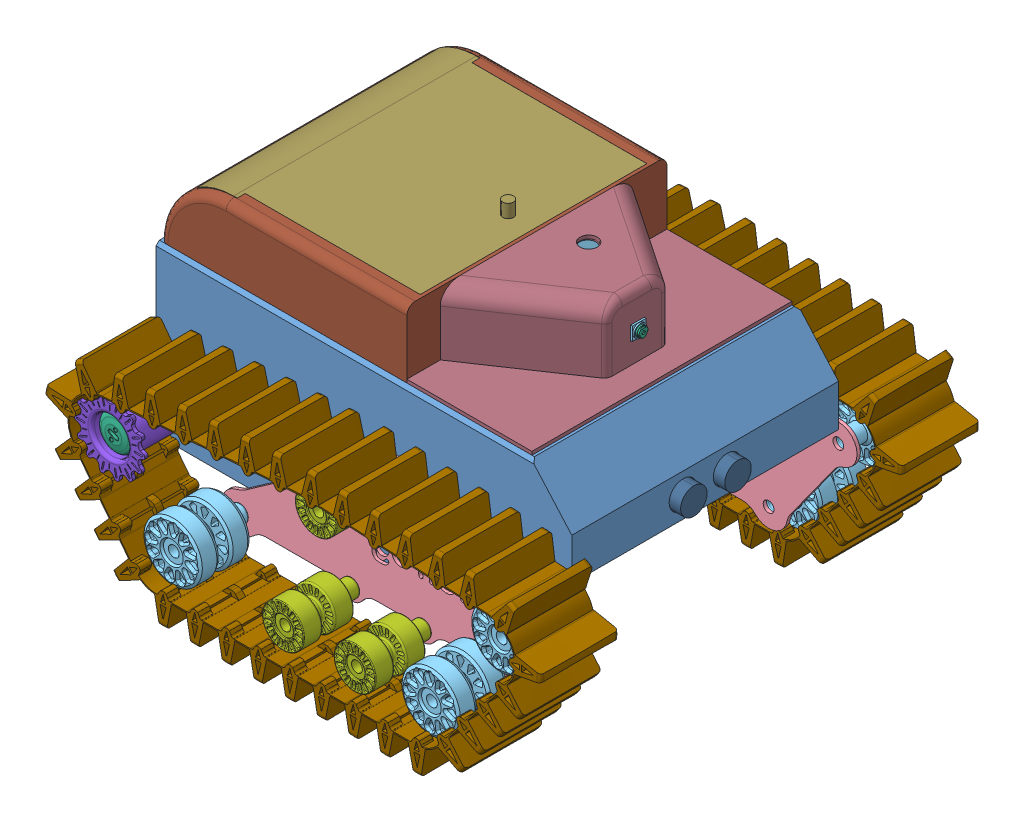
SolidWorks assembly Trial assembly, configuration Standard. Lengths in mm.
Overall size (298.01 241.17 263.94).
72 component instances, 36 part files, 43 mates.
Components (placement in the parent):
- Box-1: Box [Standard] at (-47.2891 -14.6729 181.4058) size (249.41 100 160)
- motor.step-1: motor.step [Standard] at (-130.1233 -32.1815 288.0058) x (-0.999923 0.012371 0) z (0.012371 0.999923 0) size (37.1 151.83 37.1)
- motor.step-2: motor.step [Standard] at (-129.9085 -32.1821 234.7599) x (0.999976 0.006987 0) z (-0.006987 0.999976 0) size (37.1 151.83 37.1)
- Battery-1: Battery [Standard] at (-3.4096 -17.5026 235.416) x (0.999881 0.015399 0) z (0 0 1) size (142 30 52)
- Holder final-2: Holder final [Default] at (-50.5766 -25.9238 343.4058) x (-1 0 0) z (0 0 -1) size (219.16 87.92 2)
- Idler v.1.2-1: Idler v.1.2 [Default] at (98.3421 -14.7039 369.8058) x (0.81006 -0.586348 0) z (0 0 -1) size (35 35 41.41)
- Sprocket Cap-1: Sprocket Cap [Default] at (-129.986 -21.0824 388.018) x (0.928962 -0.370176 0) z (0 0 1) size (21.5 21.5 12.71)
- Idler v.1.2-4: Idler v.1.2 [Default] at (56.5086 -68.4433 369.8058) x (-0.499777 -0.866154 0) z (0 0 -1) size (35 35 41.41)
- Idler v.1.2-5: Idler v.1.2 [Default] at (-98.3153 -68.0135 369.8058) x (-0.81006 0.586348 0) z (0 0 -1) size (35 35 41.41)
- Roller v.1.2-4: Roller v.1.2 [Default] at (-31.4914 -73.0135 369.8058) x (-0.980103 -0.198489 0) z (0 0 -1) size (25 25 41.58)
- Roller v.1.2-5: Roller v.1.2 [Default] at (-11.7449 -3.8443 369.8058) x (-0.912989 0.407984 0) z (0 0 -1) size (25 25 41.58)
- Roller v.1.2-6: Roller v.1.2 [Default] at (11.5086 -73.0135 369.8058) x (-0.63536 0.772216 0) z (0 0 -1) size (25 25 41.58)
- Sprocket1-1: Sprocket1 [Default] at (-129.986 -21.0824 388.3058) x (-0.616135 0.78764 0) z (0 0 1) size (42.28 41.35 44)
- Final Track-2: Final Track [Default] at (-129.986 -21.0824 369.7501) size (298.01 125.81 47.26)
- Holder final-3: Holder final [Default] at (-50.5766 -25.9238 181.4058) x (-1 0 0) z (0 0 -1) size (219.16 87.92 2)
- Idler v.1.2-9: Idler v.1.2 [Default] at (98.3421 -14.7039 153.0058) x (-0.81006 0.586348 0) z (0 0 1) size (35 35 41.41)
- Idler v.1.2-10: Idler v.1.2 [Default] at (-98.3153 -68.0135 153.0058) x (0.81006 -0.586348 0) z (0 0 1) size (35 35 41.41)
- Idler v.1.2-11: Idler v.1.2 [Default] at (56.5086 -68.4433 153.0058) x (0.499777 0.866154 0) z (0 0 1) size (35 35 41.41)
- Sprocket Cap-3: Sprocket Cap [Default] at (-129.986 -21.0824 134.7936) x (-0.928962 0.370176 0) z (0 0 -1) size (21.5 21.5 12.71)
- Final Track-3: Final Track [Default] at (-129.986 -21.0824 153.0615) size (298.01 125.81 47.26)
- Sprocket1-3: Sprocket1 [Default] at (-129.986 -21.0824 134.5058) x (0.616135 -0.78764 0) z (0 0 -1) size (42.28 41.35 44)
- Roller v.1.2-13: Roller v.1.2 [Default] at (11.5086 -73.0135 153.0058) x (0.201521 -0.979484 0) z (0 0 1) size (25 25 41.58)
- Roller v.1.2-14: Roller v.1.2 [Default] at (-31.4914 -73.0135 153.0058) x (0.999965 0.008424 0) z (0 0 1) size (25 25 41.58)
- Roller v.1.2-15: Roller v.1.2 [Default] at (-11.7449 -3.8443 153.0058) x (0.823373 -0.5675 0) z (0 0 1) size (25 25 41.58)
- ultrasonic-sensor.step-1: ultrasonic-sensor.step [Default] at (91.2697 5.3271 261.4058) x (0 0 -1) z (0 -1 0) size (45.3 18.15 26.45)
- Assem3-1: Assem3 [Default] at (-49.8047 45.3076 181.4058) x (1 0 0) z (0 1 0) size (148.5 156 62.98)
  - Compartment - No Tolerance-1: Compartment - No Tolerance [Default] at origin size (148.5 156 55)
  - compartment door - No tolerance-2: compartment door - No tolerance [Default] at (-59.6798 0 -0.0161) x (0 0 1) z (-1 0 0) size (14.5 145.5 129)
- Hood + Mic + Cam-1: Hood + Mic + Cam [Default] at (157.4483 -34.3077 229.7947) x (0.063713 0.2627 0.962772) z (-0.9806 0.195682 0.0115) size (169.43 108 86.1)
  - Hood-1: Hood [Default] at (-14.6815 52.7016 172.1066) x (-0.962772 0.270071 -0.0115) z (-0.063713 -0.185376 0.9806) size (156.01 55 75)
  - Mic.step-1: Mic.step [Default] at (33.7525 61.5998 155.5156) x (-0.2627 -0.944827 -0.195682) z (-0.063713 -0.185376 0.9806) size (41.3 13.35 15.1)
  - RspCamera.stp-1: RspCamera.stp [Default] at (48.9745 63.3299 120.1241) x (-0.2627 -0.944827 -0.195682) z (0.063713 0.185376 -0.9806) size (23.86 25 9.96)
    - 70521906.stp-1: 70521906.stp [Default] at (1.7167 0.8597 0.0159) size (2 2.1 0.95)
      - 70521906_01.stp-1: 70521906_01.stp [Default] at origin size (0.25 0.55 0.75)
      - 70521906_02.stp-1: 70521906_02.stp [Default] at origin size (0.25 0.55 0.75)
      - 70521906_03.stp-1: 70521906_03.stp [Default] at origin size (2 1.25 0.9)
      - 70521906_04.stp-1: 70521906_04.stp [Default] at origin size (0.25 0.55 0.75)
      - 70521906_05.stp-1: 70521906_05.stp [Default] at origin size (0.25 0.55 0.75)
      - 70521906_06.stp-1: 70521906_06.stp [Default] at origin size (0.25 0.55 0.75)
      - 70521906_07.stp-1: 70521906_07.stp [Default] at origin size (0.25 0.55 0.75)
    - PicameraPCB.stp-1: PicameraPCB.stp [Default] at (0.2393 -0.0199 0) x (-1 0 0) z (0 0 1) size (23.86 25 2.2)
    - OVA5647_Housing.stp-1: OVA5647_Housing.stp [Default] at (-2.4078 0.0859 1) x (1 0 0) z (0 -1 0) size (8 3.95 8)
    - OVA5647_Lens_FOV.stp-1: OVA5647_Lens_FOV.stp [Default] at (-2.4087 0.0921 5.963) x (1 0 0) z (0 -1 0) size (6 3.35 6)
    - ribbon_cam.stp-1: ribbon_cam.stp [Default] at (-2.4804 0.3633 1.4162) x (0 1 0) z (1 0 0) size (5.6 0.69 4.76)
    - CCD.stp-1: CCD.stp [Default] at (-2.0757 0.287 1.296) x (1 0 0) z (0 -1 0) size (8.01 0.69 8.01)
    - CAPC-0805-T0.75-BN.stp-1: CAPC-0805-T0.75-BN.stp [Default] at (4.562 5.9833 -0.0026) x (0 -1 0) z (0 0 -1) size (2.1 1.35 0.75)
    - CAPC-0805-T0.75-BN.stp-2: CAPC-0805-T0.75-BN.stp [Default] at (2.0233 10.2705 -0.0026) x (0 -1 0) z (0 0 -1) size (2.1 1.35 0.75)
    - CAPC-0402-T0.55-BN.stp-1: CAPC-0402-T0.55-BN.stp [Default] at (-2.9562 6.224 -0.2572) x (-1 0 0) z (0 -1 0) size (1.05 0.55 0.55)
    - CAPC-0402-T0.55-BN.stp-2: CAPC-0402-T0.55-BN.stp [Default] at (-2.9504 5.2898 -0.2691) x (-1 0 0) z (0 -1 0) size (1.05 0.55 0.55)
    - CAPC-0402-T0.55-BN.stp-3: CAPC-0402-T0.55-BN.stp [Default] at (4.5768 -5.1833 -0.2811) x (-1 0 0) z (0 -1 0) size (1.05 0.55 0.55)
    - CAPC-0402-T0.55-BN.stp-4: CAPC-0402-T0.55-BN.stp [Default] at (2.5547 -5.1368 -0.2811) x (-1 0 0) z (0 -1 0) size (1.05 0.55 0.55)
    - CAPC-0402-T0.55-BN.stp-5: CAPC-0402-T0.55-BN.stp [Default] at (2.6129 -9.93 -0.293) x (-1 0 0) z (0 -1 0) size (1.05 0.55 0.55)
    - CAPC-0402-T0.55-BN.stp-6: CAPC-0402-T0.55-BN.stp [Default] at (4.7286 -9.9294 -0.293) x (-1 0 0) z (0 -1 0) size (1.05 0.55 0.55)
    - CAPC-0402-T0.55-BN.stp-7: CAPC-0402-T0.55-BN.stp [Default] at (8.4068 -3.8793 -0.2811) x (-1 0 0) z (0 -1 0) size (1.05 0.55 0.55)
    - CAPC-0402-T0.55-BN.stp-8: CAPC-0402-T0.55-BN.stp [Default] at (9.0088 0.0217 -0.2796) x (0 1 0) z (-1 0 0) size (1.05 0.55 0.55)
    - CAPC-0402-T0.55-BN.stp-9: CAPC-0402-T0.55-BN.stp [Default] at (10.4284 2.6731 -0.3022) x (0 1 0) z (-1 0 0) size (1.05 0.55 0.55)
    - CAPC-0402-T0.55-BN.stp-10: CAPC-0402-T0.55-BN.stp [Default] at (8.2321 1.3259 -0.2838) x (1 0 0) z (0 1 0) size (1.05 0.55 0.55)
    - RESC-0402.stp-1: RESC-0402.stp [Default] at (3.7919 0.0148 -0.0114) x (1 0 0) z (0 0 -1) size (1.05 0.55 0.4)
    - RESC-0402.stp-2: RESC-0402.stp [Default] at (4.1232 2.6296 -0.0028) x (0 -1 0) z (0 0 -1) size (1.05 0.55 0.4)
    - RESC-0402.stp-3: RESC-0402.stp [Default] at (10.5883 -6.2795 -0.0019) x (0 1 0) z (0 0 -1) size (1.05 0.55 0.4)
    - RESC-0603.stp-1: RESC-0603.stp [Default] at (-2.6191 7.0617 -0.0121) x (1 0 0) z (0 0 -1) size (1.7 0.9 0.55)
    - RESC-0603.stp-2: RESC-0603.stp [Default] at (-3.4466 3.0018 -0.0048) x (0 -1 0) z (0 0 -1) size (1.7 0.9 0.55)
    - RESC-1210.stp-1: RESC-1210.stp [Default] at (2.2265 5.9002 -0.0068) x (0 -1 0) z (0 0 -1) size (3.3 2.7 0.6)
    - c-1-1734248-5-e-raspberry_display.stp-1: c-1-1734248-5-e-raspberry_display.stp [Default] at (-10.6651 0.0449 -1.5) x (0 -1 0) z (-1 0 0) size (22.4 3.22 5.68)
    - SOT23-5.stp-1: SOT23-5.stp [Default] at (4.2989 9.8879 0.5457) x (0 -1 0) z (0 0 -1) size (2.84 3.01 1.19)
    - SOT23-5.stp-2: SOT23-5.stp [Default] at (3.5194 -3.2493 0.04) x (-1 0 0) z (0 0 -1) size (2.84 3.01 1.19)
    - SOT23-5.stp-3: SOT23-5.stp [Default] at (3.5816 -8.055 0.0206) x (-1 0 0) z (0 0 -1) size (2.84 3.01 1.19)
    - KX7 SMD Quartz Crystal Resonator 3.2x2.5mm.stp-1: KX7 SMD Quartz Crystal Resonator 3.2x2.5mm.stp [Default] at (9.9746 -4.9221 0.0339) x (-1 0 0) z (0 -1 0) size (3.2 0.6 2.5)
    - c6aaa.stp-1: c6aaa.stp [Default] at (0.0643 0.0942 0) x (1 0 0) z (0 0 -1) size (2 2.99 0.6)
    - 4pin_smd.stp-1: 4pin_smd.stp [Default] at (0.027 0.0676 0) x (1 0 0) z (0 0 -1) size (1.29 1 0.47)
    - 4pin_smd.stp-2: 4pin_smd.stp [Default] at (-0.0093 -6.0092 -0.0198) x (1 0 0) z (0 0 -1) size (1.29 1 0.47)
    - 4pin_smd.stp-3: 4pin_smd.stp [Default] at (0.0326 -3.0068 -0.0235) x (1 0 0) z (0 0 -1) size (1.29 1 0.47)
Mates (geometry in assembly coordinates):
- Concentric1: concentric: circle of Box-1; cylinder of motor.step-1 through (-129.986 -21.0824 361.8058) axis (0 0 -1) radius 2.95
- Concentric2: concentric anti-aligned: circle of Box-1; circle of motor.step-2
- Coincident1: coincident: plane of Box-1 through (-150.986 -52.6924 341.4058) normal (0 1 0); line of Battery-1 through (-95.6615 -52.6924 287.416) axis (0 0 -1)
- Coincident4: coincident anti-aligned: plane of Box-1 through (-47.2891 -14.6729 341.4058) normal (0 0 1); plane of Holder final Opposite-1 through (98.3421 -14.7039 341.4058) normal (0 0 -1)
- Coincident14: coincident anti-aligned: plane of Box-1 through (-47.2891 -14.6729 339.4058) normal (0 0 -1); plane of motor.step-1 through (-130.1233 -32.1815 339.4058) normal (0 0 1)
- Concentric10: concentric aligned: cylinder of Holder final Opposite-1 through (98.3421 -14.7039 341.4058) axis (0 0 1) radius 3.25; cylinder of Idler v.1.2-1 through (98.3421 -14.7039 384.8058) axis (0 0 1) radius 3.25
- Coincident16: coincident anti-aligned: plane of Holder final Opposite-1 through (98.3421 -14.7039 343.4058) normal (0 0 1); circle of Idler v.1.2-1
- Concentric12: concentric aligned: cylinder of Holder final Opposite-1 through (-98.3153 -68.0135 341.4058) axis (0 0 1) radius 3.25; cylinder of Idler v.1.2-5 through (-98.3153 -68.0135 384.8058) axis (0 0 1) radius 3.25
- Coincident18: coincident anti-aligned: plane of Holder final Opposite-1 through (98.3421 -14.7039 343.4058) normal (0 0 1); circle of Idler v.1.2-5
- Concentric14: concentric aligned: cylinder of Holder final Opposite-1 through (56.5086 -68.4433 341.4058) axis (0 0 1) radius 3.25; cylinder of Idler v.1.2-4 through (56.5086 -68.4433 384.8058) axis (0 0 1) radius 3.25
- Coincident19: coincident anti-aligned: plane of Holder final Opposite-1 through (98.3421 -14.7039 343.4058) normal (0 0 1); circle of Idler v.1.2-4
- Concentric15: concentric anti-aligned: cylinder of Holder final Opposite-1 through (-31.4914 -73.0135 341.4058) axis (0 0 1) radius 3.25; cylinder of Roller v.1.2-4 through (-31.4914 -73.0135 354.8058) axis (0 0 -1) radius 3.25
- Coincident20: coincident anti-aligned: plane of Holder final Opposite-1 through (98.3421 -14.7039 343.4058) normal (0 0 1); circle of Roller v.1.2-4
- Concentric16: concentric anti-aligned: cylinder of Holder final Opposite-1 through (-11.7449 -3.8443 341.4058) axis (0 0 1) radius 3.25; cylinder of Roller v.1.2-5 through (-11.7449 -3.8443 354.8058) axis (0 0 -1) radius 3.25
- Coincident21: coincident anti-aligned: plane of Holder final Opposite-1 through (98.3421 -14.7039 343.4058) normal (0 0 1); circle of Roller v.1.2-5
- Concentric17: concentric anti-aligned: cylinder of Holder final Opposite-1 through (11.5086 -73.0135 341.4058) axis (0 0 1) radius 3.25; cylinder of Roller v.1.2-6 through (11.5086 -73.0135 354.8058) axis (0 0 -1) radius 3.25
- Coincident22: coincident anti-aligned: plane of Holder final Opposite-1 through (98.3421 -14.7039 343.4058) normal (0 0 1); circle of Roller v.1.2-6
- Concentric18: concentric anti-aligned: cylinder of Box-1 through (18.2551 -6.8037 181.4058) axis (0 0 1) radius 1.4; cylinder of Holder final Opposite-1 through (18.2551 -6.8037 343.4058) axis (0 0 -1) radius 1.4
- Concentric19: concentric anti-aligned: cylinder of Box-1 through (-31.4914 -33.4433 181.4058) axis (0 0 1) radius 1.4; cylinder of Holder final Opposite-1 through (-31.4914 -33.4433 343.4058) axis (0 0 -1) radius 1.4
- Coincident23: coincident anti-aligned: plane of motor.step-1 through (-129.986 -21.0824 346.3058) normal (0 0 1); plane of Sprocket1-1 through (-129.986 -21.0824 346.3058) normal (0 0 -1)
- Concentric21: concentric anti-aligned: cylinder of motor.step-1 through (-129.986 -21.0824 361.8058) axis (0 0 -1) radius 2.95; cylinder of Sprocket1-1 through (-129.986 -21.0824 346.3058) axis (0 0 1) radius 3.025
- Concentric22: concentric aligned: cylinder of Sprocket Cap-1 through (-129.986 -21.0824 386.1355) axis (0 0 -1) radius 7.25; cylinder of Sprocket1-1 through (-129.986 -21.0824 353.3058) axis (0 0 -1) radius 11
- Coincident24: coincident anti-aligned: circle of Sprocket Cap-1; plane of Sprocket1-1 through (-129.986 -21.0824 384.3058) normal (0 0 1)
- Concentric23: concentric anti-aligned: cylinder of Idler v.1.2-1 through (98.3421 -14.7039 384.8058) axis (0 0 1) radius 17.5; cylinder of Belt1-1-2 through (98.3421 -14.7039 393.2501) axis (0 0 -1) radius 17.6
- Concentric24: concentric anti-aligned: cylinder of Sprocket1-1 through (-129.986 -21.0824 350.3058) axis (0 0 1) radius 12; cylinder of Belt1-1-2 through (-129.986 -21.0824 393.2501) axis (0 0 -1) radius 21.4
- Parallel2: parallel anti-aligned: plane of Sprocket1-1 through (-147.414 -14.8764 390.3058) normal (-0.725341 -0.68839 0); plane of Belt1-1-2 through (-149.0336 -13.751 386.2501) normal (0.725341 0.68839 0)
- Coincident32: coincident anti-aligned: circle of Box-1; circle of Holder final-3
- Coincident34: coincident anti-aligned: circle of Box-1; circle of Holder final-3
- Coincident35: coincident aligned: cylinder of Holder final-3 through (11.5086 -73.0135 179.4058) axis (0 0 1) radius 3.25; circle of Roller v.1.2-13
- Concentric27: concentric aligned: cylinder of Holder final-3 through (-31.4914 -73.0135 179.4058) axis (0 0 1) radius 3.25; cylinder of Roller v.1.2-14 through (-31.4914 -73.0135 168.0058) axis (0 0 1) radius 3.25
- Coincident36: coincident anti-aligned: plane of Holder final-3 through (98.3421 -14.7039 179.4058) normal (0 0 -1); circle of Roller v.1.2-14
- Coincident37: coincident anti-aligned: plane of Holder final-3 through (98.3421 -14.7039 179.4058) normal (0 0 -1); circle of Roller v.1.2-13
- Concentric28: concentric aligned: cylinder of Holder final-3 through (-11.7449 -3.8443 179.4058) axis (0 0 1) radius 3.25; cylinder of Roller v.1.2-15 through (-11.7449 -3.8443 168.0058) axis (0 0 1) radius 3.25
- Coincident38: coincident anti-aligned: plane of Holder final-3 through (98.3421 -14.7039 179.4058) normal (0 0 -1); circle of Roller v.1.2-15
- Concentric29: concentric anti-aligned: circle of Box-1; cylinder of ultrasonic-sensor.step-1 through (104.9197 5.3271 248.1558) axis (-1 0 0) radius 7.95
- Concentric30: concentric anti-aligned: cylinder of Box-1 through (95.4197 5.3271 274.6558) axis (1 0 0) radius 8.35; cylinder of ultrasonic-sensor.step-1 through (104.9197 5.3271 274.6558) axis (-1 0 0) radius 7.95
- Coincident39: coincident anti-aligned: plane of Box-1 through (96.4197 4.0812 341.4058) normal (-1 0 0); plane of ultrasonic-sensor.step-1 through (96.4197 12.6771 264.6058) normal (1 0 0)
- Coincident47: coincident anti-aligned: plane of Box-1 through (93.728 45.3076 198.4058) normal (0 -0.707107 0.707107); plane of Assem3-1/Compartment-1 through (19.014 45.3076 198.4058) normal (0 0.707107 -0.707107)
- Coincident48: coincident anti-aligned: plane of Box-1 through (93.728 45.3076 324.4058) normal (0 -0.707107 -0.707107); plane of Assem3-1/Compartment-1 through (19.014 45.3076 324.4058) normal (0 0.707107 0.707107)
- Coincident49: coincident anti-aligned: line of Box-1 through (-150.986 30.3076 183.4058) axis (0 0 1); line of Assem3-1/Compartment-1 through (-150.986 30.3076 339.4058) axis (0 0 -1)
- Coincident50: coincident anti-aligned: plane of Box-1 through (93.728 45.3076 198.4058) normal (0 -0.707107 0.707107); plane of Hood + Mic + Cam-1/Hood-1 through (72.5148 45.3076 198.4058) normal (0 0.707107 -0.707107)
- Coincident51: coincident anti-aligned: plane of Box-1 through (93.728 45.3076 324.4058) normal (0 -0.707107 -0.707107); plane of Hood + Mic + Cam-1/Hood-1 through (72.5148 45.3076 324.4058) normal (0 0.707107 0.707107)
- Coincident52: coincident anti-aligned: plane of Box-1 through (72.5148 45.3076 341.4058) normal (-1 0 0); plane of Hood + Mic + Cam-1/Hood-1 through (72.5148 30.3076 339.4058) normal (1 0 0)
